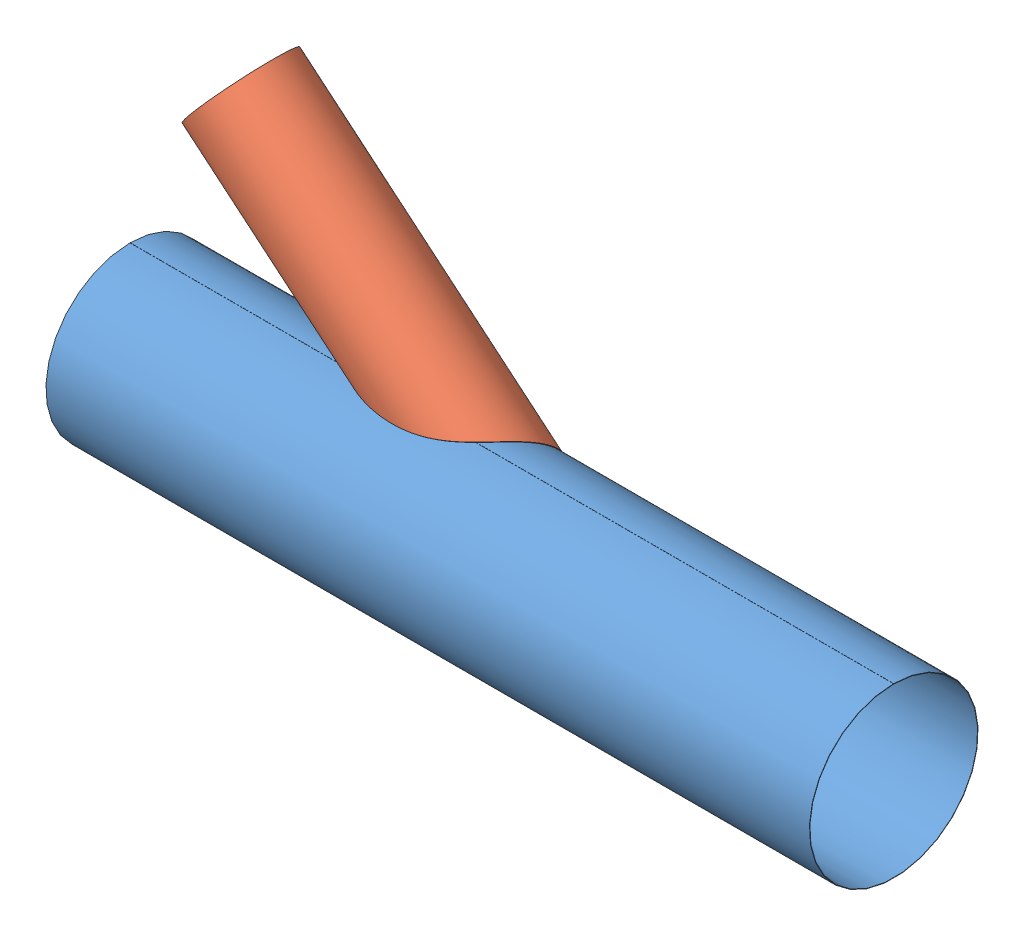
SolidWorks assembly test piquage angle a regler avec deplier2, configuration Défaut. Lengths in mm.
Overall size (1000 497.42 223.51).
3 component instances, 3 part files, 9 mates.
Components (placement in the parent):
- Pièce4-1: Pièce4 [Défaut] at (-500 0 0) x (0 0 -1) z (1 0 0)
- tube dia 100-4: tube dia 100 [Défaut] x (0 0 -1) z (1 0 0) size (221 221 1000)
- tube dia 80-4: tube dia 80 [Défaut] at (-389.8904 327.1569 -35) x (-0.145225 -0.173072 -0.974144) z (-0.766044 0.642788 0) size (130.01 130.01 449.77)
Mates (geometry in assembly coordinates):
- Sur place1: in place: plane of Pièce4-1 through (-500 0 0) normal (1 0 0); moOrthogonalPlaneRef_w of Pièce4-1 through (-55 -500 0) axis (0 0 1); plane of Pièce4-1 through (-500 0 0) normal (0 0 -1); unknown of Pièce4-1
- Coïncidente15: coincident aligned: plane of Pièce4-1; plane of assembly
- Coïncidente16: coincident aligned: plane of Pièce4-1; moOrthogonalPlaneRef_w of assembly
- Coïncidente17: coincident anti-aligned: plane of Pièce4-1 through (-500 0 0) normal (0 0 -1); moOrthogonalPlaneRef_w of assembly
- Coïncidente18: coordinate: point of tube dia 100-4; point of assembly
- Coaxiale14: concentric anti-aligned: cylinder of tube dia 100-4 through (500 0 0) axis (-1 0 0) radius 110; line of assembly
- Parallèle4: parallel aligned: line of tube dia 80-4 through (-227.9379 108.6349 -20.2164) axis (-0.766044 0.642788 0); line of assembly
- Distance4: distance = 66.4466 mm: line of assembly; line of tube dia 80-4 through (-227.9379 108.6349 -20.2164) axis (-0.766044 0.642788 0)
- Coaxiale15: concentric aligned: cylinder of tube dia 80-4 through (347.8234 -291.8585 -35) axis (-0.766044 0.642788 0) radius 64.5; line of assembly
